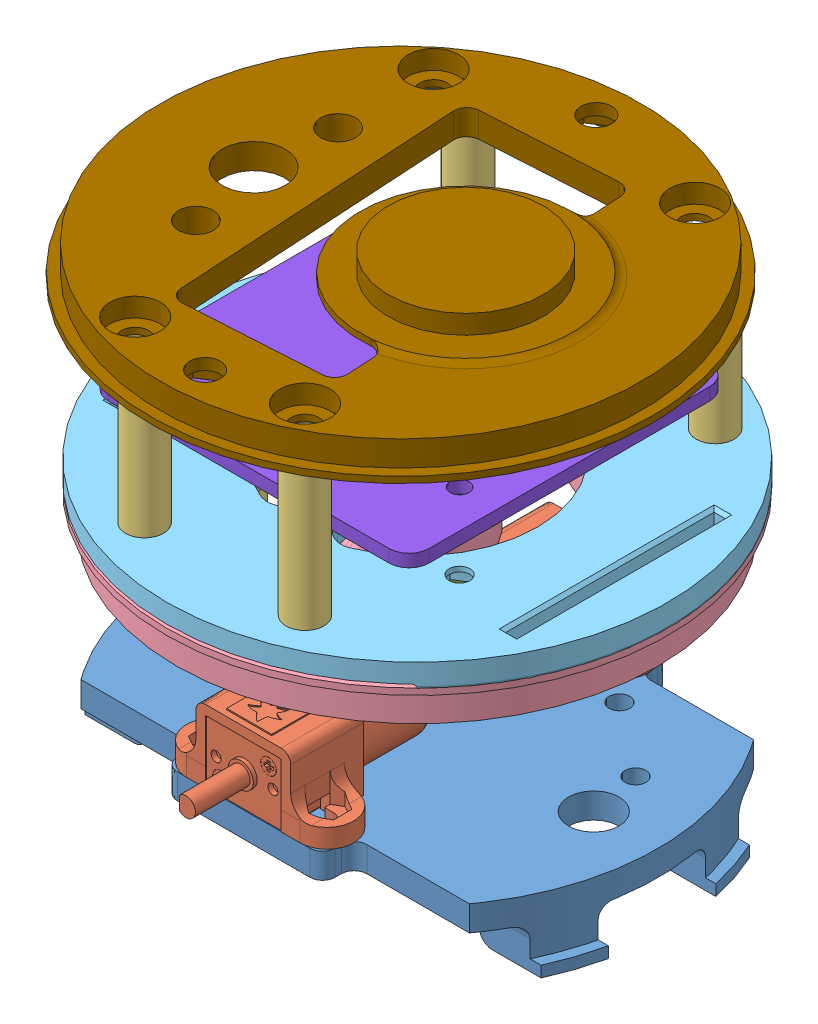
SolidWorks assembly _bot, configuration Default. Lengths in mm.
Overall size (84 77.55 84).
14 component instances, 9 part files, 27 mates.
Components (placement in the parent):
- bottom_cap-1: bottom_cap [Default] at (0 1.2937 0) x (0 1 0) z (0 0 -1) size (10.5 77.53 55)
- DC_motor-1: DC_motor [Default] at (0 10.2937 -18.35) x (0 0 -1) z (1 0 0) size (35.27 11.7 26.5)
- DC_motor-2: DC_motor [Default] at (0 10.2937 18.35) x (0 0 1) z (-1 0 0) size (35.27 11.7 26.5)
- spacer_25-1: spacer_25 [Default] at (-27.94 30.2937 0) x (1 0 0) z (0 -1 0) size (6 6 25)
- base_mod-1: base_mod [Default] at (0 30.2937 0) x (0 0 -1) z (0 1 0) size (79.38 79.38 19.57)
- base_2-1: base_2 [Default] at (0 36.8455 0) x (0 0 -1) z (0 1 0) size (79.38 79.38 4)
- pot.0001-1: pot.0001 [Default] at (0 46.1955 0) x (0 0 -1) z (0 -1 0) size (26.04 19.05 28.57)
- clamp-1: clamp [Default] at (-0.095 30.2937 -0.14) x (0 0 -1) z (0 -1 0) size (16.47 7.66 13.57)
- breadboard_2_inch-1: breadboard_2_inch [Default] at (0 51.8455 1.3) x (0 0 1) z (0 -1 0) size (50.8 50.8 2)
- spacer_25-2: spacer_25 [Default] at (-12.7 64.8455 30.48) x (0 0 -1) z (0 -1 0) size (6 6 25)
- spacer_25-3: spacer_25 [Default] at (12.7 64.8455 30.48) x (0 0 -1) z (0 -1 0) size (6 6 25)
- spacer_25-4: spacer_25 [Default] at (19.5699 64.8455 -27.6) x (0 0 -1) z (0 -1 0) size (6 6 25)
- spacer_25-5: spacer_25 [Default] at (-19.5699 64.8455 -27.6) x (0 0 -1) z (0 -1 0) size (6 6 25)
- top_ring-1: top_ring [Default] at (-1.81 68.8455 0.8189) x (-0.99819 0 0.060136) z (0.060136 0 0.99819) size (79.38 8.5 79.38)
Mates (geometry in assembly coordinates):
- Concentric1: concentric aligned: cylinder of bottom_cap-1 through (9 5.2937 -23.3) axis (0 -1 0) radius 1.15; circle of DC_motor-1
- Coincident2: coincident anti-aligned: plane of bottom_cap-1 through (0 5.2937 0) normal (0 1 0); plane of DC_motor-1 through (3.3166 5.2937 -3.35) normal (0 -1 0)
- Concentric3: concentric anti-aligned: cylinder of bottom_cap-1 through (9 5.2937 23.3) axis (0 1 0) radius 1.15; circle of DC_motor-2
- Coincident8: coincident anti-aligned: plane of bottom_cap-1 through (0 5.2937 0) normal (0 1 0); plane of DC_motor-2 through (-3.3166 5.2937 3.35) normal (0 -1 0)
- Coincident12: coincident aligned: circle of bottom_cap-1; plane of spacer_25-1 through (-27.94 5.2937 0) normal (0 -1 0)
- Concentric6: concentric aligned: circle of bottom_cap-1; circle of spacer_25-1
- Coincident13: coincident aligned: plane of spacer_25-1 through (-27.94 30.2937 0) normal (0 1 0); circle of base_mod-1
- Concentric7: concentric anti-aligned: circle of spacer_25-1; circle of base_mod-1
- Rotate Base: concentric aligned: circle of base_mod-1; cylinder of pot.0001-1 through (0 30.1935 0) axis (0 -1 0) radius 3.175
- Concentric9: concentric aligned: cylinder of base_2-1 through (0 39.8455 0) axis (0 -1 0) radius 5.2388; cylinder of pot.0001-1 through (0 39.8455 0) axis (0 -1 0) radius 4.7625
- Coincident17: coincident anti-aligned: plane of base_2-1 through (0 39.8455 0) normal (0 1 0); plane of pot.0001-1 through (0 39.8455 0) normal (0 -1 0)
- Coincident18: coincident anti-aligned: plane of base_mod-1 through (0 19.2207 0) normal (0 1 0); plane of pot.0001-1 through (0 19.2207 0) normal (0 -1 0)
- Concentric10: concentric aligned: cylinder of base_mod-1 through (0.5 23.5072 -5.8161) axis (-1 0 0) radius 1.1; cylinder of clamp-1 through (8.16 23.5072 -5.8161) axis (-1 0 0) radius 1.2
- Coincident19: coincident anti-aligned: plane of base_mod-1 through (0.5 30.2937 3.3924) normal (1 0 0); plane of clamp-1 through (0.5 30.2937 -3.2587) normal (-1 0 0)
- Concentric12: concentric aligned: cylinder of base_2-1 through (19.5699 39.8455 -27.6) axis (0 -1 0) radius 2.2; cylinder of spacer_25-4 through (19.5699 64.8455 -27.6) axis (0 -1 0) radius 3
- Coincident20: coincident anti-aligned: plane of base_2-1 through (0 39.8455 0) normal (0 1 0); circle of spacer_25-4
- Concentric13: concentric aligned: cylinder of base_2-1 through (-19.5699 39.8455 -27.6) axis (0 -1 0) radius 2.2; cylinder of spacer_25-5 through (-19.5699 64.8455 -27.6) axis (0 -1 0) radius 3
- Coincident21: coincident anti-aligned: plane of base_2-1 through (0 39.8455 0) normal (0 1 0); plane of spacer_25-5 through (-19.5699 39.8455 -27.6) normal (0 -1 0)
- Concentric15: concentric aligned: cylinder of base_2-1 through (12.7 39.8455 30.48) axis (0 -1 0) radius 2.2; cylinder of spacer_25-3 through (12.7 64.8455 30.48) axis (0 -1 0) radius 3
- Coincident23: coincident anti-aligned: plane of base_2-1 through (0 39.8455 0) normal (0 1 0); plane of spacer_25-3 through (12.7 39.8455 30.48) normal (0 -1 0)
- Concentric16: concentric aligned: circle of base_2-1; cylinder of spacer_25-2 through (-12.7 64.8455 30.48) axis (0 -1 0) radius 3
- Coincident24: coincident anti-aligned: plane of base_2-1 through (0 39.8455 0) normal (0 1 0); circle of spacer_25-2
- Concentric24: concentric anti-aligned: circle of spacer_25-3; circle of top_ring-1
- Coincident36: coincident anti-aligned: plane of spacer_25-3 through (12.7 64.8455 30.48) normal (0 1 0); plane of top_ring-1 through (-1.81 64.8455 0.8189) normal (0 -1 0)
- Lock1: lock: unknown of breadboard_2_inch-1; unknown of top_ring-1
- Symmetric1: symmetric aligned: plane of DC_motor-1 through (6 5.2937 -27.35) normal (0 0 -1); plane of DC_motor-2 through (-6 5.2937 27.35) normal (0 0 1)
- Symmetric2: symmetric aligned: plane of DC_motor-2 through (7.5 8.2937 27.55) normal (1 0 0); plane of DC_motor-2 through (-7.5 16.7937 27.55) normal (-1 0 0)
